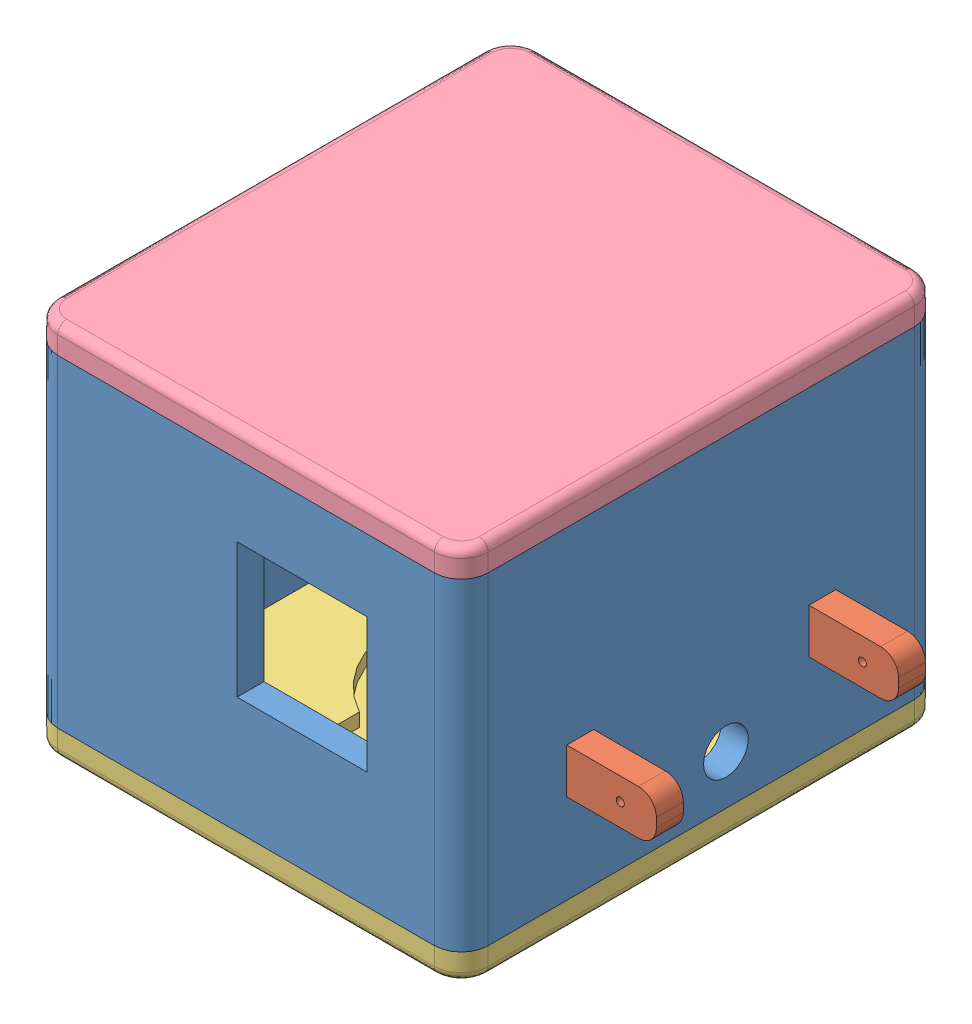
SolidWorks assembly System Assembly, configuration Default. Lengths in mm.
Overall size (68 42 53.5).
7 component instances, 4 part files, 12 mates.
Components (placement in the parent):
- Side_Walls-1: Side_Walls [Default] at (13.9614 19.688 49.8287) size (48 36 53.5)
- Watch_Lug-1: Watch_Lug [Default] at (37.9614 29.688 61.8287) x (1 0 0) z (0 -1 0) size (10 3 5)
- Watch_Lug-2: Watch_Lug [Default] at (-10.0386 29.688 64.8287) x (-1 0 0) z (0 -1 0) size (10 3 5)
- Watch_Lug-3: Watch_Lug [Default] at (-10.0386 34.688 34.8287) x (-1 0 0) z (0 1 0) size (10 3 5)
- Watch_Lug-4: Watch_Lug [Default] at (37.9614 29.688 34.8287) x (1 0 0) z (0 -1 0) size (10 3 5)
- Bottom_Layer-1: Bottom_Layer [Default] at (13.9614 16.688 49.8287) size (48 3 53.5)
- Part_2_3D_Print_Top_Cover-1: Part_2_3D_Print_Top_Cover [Default] at (13.9614 55.688 49.8287) size (48 3 53.5)
Mates (geometry in assembly coordinates):
- Coincident1: coincident: line of Side_Walls-1 through (37.9614 29.688 34.8287) axis (0 1 0); line of Watch_Lug-4 through (37.9614 34.688 34.8287) axis (0 -1 0)
- Coincident2: coincident: line of Side_Walls-1 through (37.9614 34.688 37.8287) axis (0 0 -1); line of Watch_Lug-4 through (37.9614 34.688 37.8287) axis (0 0 -1)
- Coincident3: coincident: line of Side_Walls-1 through (37.9614 29.688 61.8287) axis (0 1 0); line of Watch_Lug-1 through (37.9614 34.688 61.8287) axis (0 -1 0)
- Coincident4: coincident: line of Side_Walls-1 through (37.9614 34.688 64.8287) axis (0 0 -1); line of Watch_Lug-1 through (37.9614 34.688 64.8287) axis (0 0 -1)
- Coincident8: coincident: line of Side_Walls-1 through (-10.0386 29.688 61.8287) axis (0 0 1); line of Watch_Lug-2 through (-10.0386 29.688 61.8287) axis (0 0 1)
- Coincident9: coincident: line of Side_Walls-1 through (-10.0386 34.688 61.8287) axis (0 0 1); line of Watch_Lug-2 through (-10.0386 34.688 61.8287) axis (0 0 1)
- Coincident10: coincident: line of Side_Walls-1 through (-10.0386 34.688 34.8287) axis (0 0 1); line of Watch_Lug-3 through (-10.0386 34.688 37.8287) axis (0 0 -1)
- Coincident11: coincident: line of Side_Walls-1 through (-10.0386 34.688 37.8287) axis (0 -1 0); line of Watch_Lug-3 through (-10.0386 29.688 37.8287) axis (0 1 0)
- Coincident12: coincident: line of Side_Walls-1 through (-7.0386 19.688 76.5787) axis (1 0 0); line of Bottom_Layer-1 through (-7.0386 19.688 76.5787) axis (1 0 0)
- Coincident13: coincident: line of Side_Walls-1 through (37.9614 19.688 73.5787) axis (0 0 -1); line of Bottom_Layer-1 through (37.9614 19.688 73.5787) axis (0 0 -1)
- Coincident14: coincident: line of Side_Walls-1 through (37.9614 55.688 73.5787) axis (0 0 -1); line of Part_2_3D_Print_Top_Cover-1 through (37.9614 55.688 73.5787) axis (0 0 -1)
- Coincident15: coincident: line of Side_Walls-1 through (34.9614 55.688 23.0787) axis (-1 0 0); line of Part_2_3D_Print_Top_Cover-1 through (34.9614 55.688 23.0787) axis (-1 0 0)
